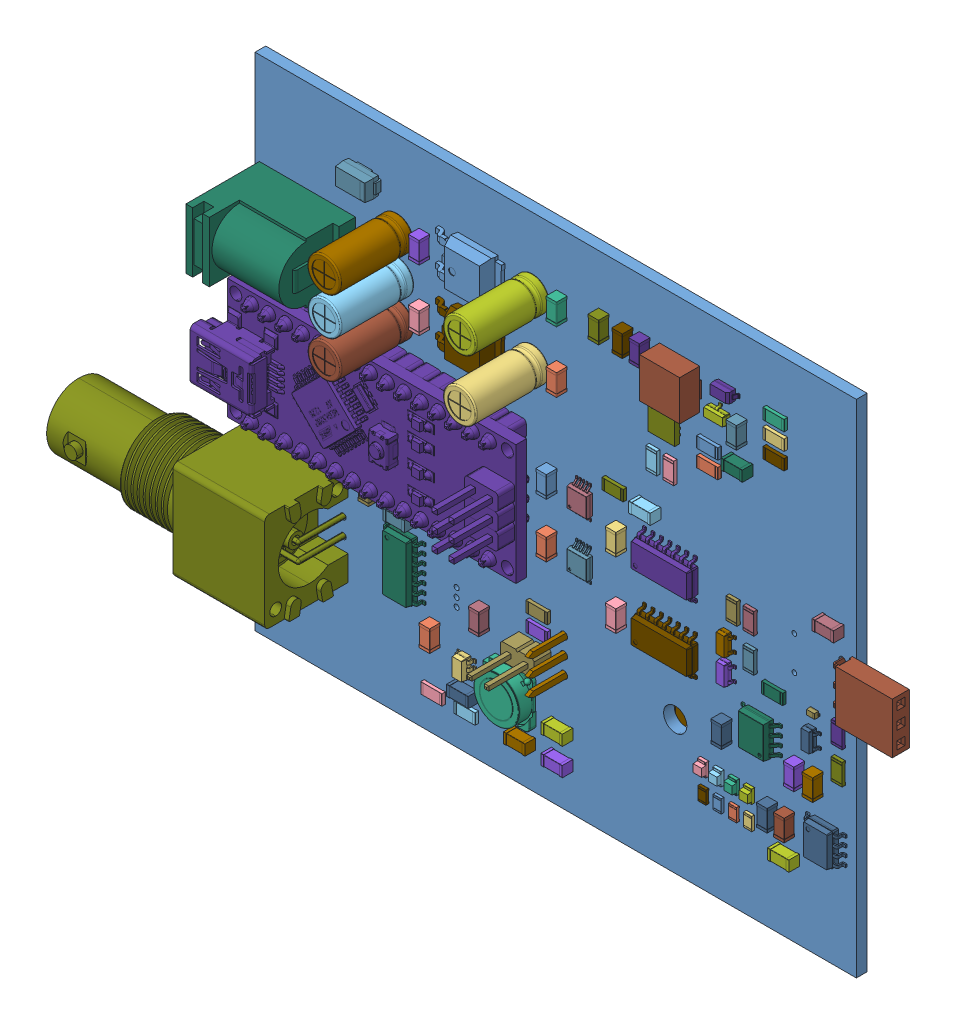
SolidWorks assembly PCB assembly, configuration Domyślna. Lengths in mm.
Overall size (117.64 75 20.3).
95 component instances, 91 part files, 0 mates.
Components (placement in the parent):
- PCB assembly.step-1: PCB assembly.step [Domyślna] at origin size (117.64 75 20.3)
  - Board_Geoms_e78a.step-1: Board_Geoms_e78a.step [Domyślna] at origin size (90 75 1.6)
    - Pcb_e78a.step-1: Pcb_e78a.step [Domyślna] at (-104.194 136.428 0) size (90 75 1.6)
    - PCB_Sketch_e78a.step-1: PCB_Sketch_e78a.step [Domyślna] at origin (suppressed, hidden)
  - Step_Models_e78a.step-1: Step_Models_e78a.step [Domyślna] at origin size (117.64 63.77 20.3)
    - Top_e78a.step-1: Top_e78a.step [Domyślna] at origin size (117.64 63.77 20.3)
      - C31_C_1206_3216Metric_5F0E55A1.step-1: C31_C_1206_3216Metric_5F0E55A1.step [Domyślna] at (26.924 3.302 0) x (0 -1 0) z (0 0 1) size (3.2 1.6 1.6)
      - IC12_SOT_23_6_5F31C27B.step-1: IC12_SOT_23_6_5F31C27B.step [Domyślna] at (31.75 1.651 0) x (-1 0 0) z (0 0 1) size (2.8 2.9 1.55)
      - R23_R_1206_3216Metric_5F31C265.step-1: R23_R_1206_3216Metric_5F31C265.step [Domyślna] at (26.924 -4.445 0) size (3.2 1.6 0.55)
      - R22_R_1206_3216Metric_5F31DD4A.step-1: R22_R_1206_3216Metric_5F31DD4A.step [Domyślna] at (31.877 -4.445 0) x (-1 0 0) z (0 0 1) size (3.2 1.6 0.55)
      - L2_Sf_fd_sp_5F31CDB4[2].step-1: L2_Sf_fd_sp_5F31CDB4[2].step [Domyślna] at (38.608 1.651 0.0508) size (7 7 2.5)
      - C36_C_1206_3216Metric_5F31B990.step-1: C36_C_1206_3216Metric_5F31B990.step [Domyślna] at (45.974 0.381 0) size (3.2 1.6 1.6)
      - C35_C_1206_3216Metric_5F31B97F.step-1: C35_C_1206_3216Metric_5F31B97F.step [Domyślna] at (45.974 -3.683 0) size (3.2 1.6 1.6)
      - C34_C_1206_3216Metric_5F31B96E.step-1: C34_C_1206_3216Metric_5F31B96E.step [Domyślna] at (40.386 -3.683 0) x (-1 0 0) z (0 0 1) size (3.2 1.6 1.6)
      - C33_C_1206_3216Metric_5F31B95D.step-1: C33_C_1206_3216Metric_5F31B95D.step [Domyślna] at (31.877 -1.778 0) x (-1 0 0) z (0 0 1) size (3.2 1.6 1.6)
      - C32_C_1206_3216Metric_5F2DB7B1.step-1: C32_C_1206_3216Metric_5F2DB7B1.step [Domyślna] at (5.334 24.384 0) x (-1 0 0) z (0 0 1) size (3.2 1.6 1.6)
      - R21_R_1206_3216Metric_5F2CE966.step-1: R21_R_1206_3216Metric_5F2CE966.step [Domyślna] at (42.672 13.97 0) size (3.2 1.6 0.55)
      - IC8_DS1124U-25+_5F0C9A39.step-1: IC8_DS1124U-25+_5F0C9A39.step [Domyślna] at (49.222 31.78 0) x (0 1 0) z (0 0 1) size (4.9 3 1.1)
      - IC7_DS1124U-25+_5F0C50CD.step-1: IC7_DS1124U-25+_5F0C50CD.step [Domyślna] at (49.222 23.652 0) x (0 1 0) z (0 0 1) size (4.9 3 1.1)
      - IC2_TLV3501AIDR_5F0DC31C.step-1: IC2_TLV3501AIDR_5F0DC31C.step [Domyślna] at (75.944 15.19 0) x (-1 0 0) z (0 0 1) size (6 4.9 1.75)
      - IC1_MAX1932ETC+_5F0DC301.step-1: IC1_MAX1932ETC+_5F0DC301.step [Domyślna] at (61.614 48.076 0) size (4.1 4.1 0.8)
      - D1_BAT46W-E3-08_5F0B6668.step-1: D1_BAT46W-E3-08_5F0B6668.step [Domyślna] at (70.758 56.712 0) x (-1 0 0) z (0 0 1) size (3.7 1.55 1.35)
      - R20_R_0805_2012Metric_5F2C1AB9.step-1: R20_R_0805_2012Metric_5F2C1AB9.step [Domyślna] at (67.31 2.54 0) x (0 -1 0) z (0 0 1) size (2 1.2 0.45)
      - R19_R_0805_2012Metric_5F2C1B19.step-1: R19_R_0805_2012Metric_5F2C1B19.step [Domyślna] at (69.596 2.54 0) x (0 -1 0) z (0 0 1) size (2 1.2 0.45)
      - R16_R_0805_2012Metric_5F2C1B49.step-1: R16_R_0805_2012Metric_5F2C1B49.step [Domyślna] at (71.882 2.54 0) x (0 -1 0) z (0 0 1) size (2 1.2 0.45)
      - R13_R_0805_2012Metric_5F2C1AE9.step-1: R13_R_0805_2012Metric_5F2C1AE9.step [Domyślna] at (74.168 2.54 0) x (0 -1 0) z (0 0 1) size (2 1.2 0.45)
      - D8_LED_0805_2012Metric_5F2C1BB1.step-1: D8_LED_0805_2012Metric_5F2C1BB1.step [Domyślna] at (67.31 6.096 0) x (0 1 0) z (0 0 1) size (2 1.25 1.1)
      - D7_LED_0805_2012Metric_5F2C1BE7.step-1: D7_LED_0805_2012Metric_5F2C1BE7.step [Domyślna] at (69.596 6.096 0) x (0 1 0) z (0 0 1) size (2 1.25 1.1)
      - D6_LED_0805_2012Metric_5F2C1B7B.step-1: D6_LED_0805_2012Metric_5F2C1B7B.step [Domyślna] at (71.882 6.096 0) x (0 1 0) z (0 0 1) size (2 1.25 1.1)
      - D5_LED_0805_2012Metric_5F2B9F6D.step-1: D5_LED_0805_2012Metric_5F2B9F6D.step [Domyślna] at (74.168 6.096 0) x (0 1 0) z (0 0 1) size (2 1.25 1.1)
      - R10_R_1206_3216Metric_5F2BA4CF.step-1: R10_R_1206_3216Metric_5F2BA4CF.step [Domyślna] at (42.672 11.43 0) size (3.2 1.6 0.55)
      - Q5_TO-220-3_Horizontal_TabUp_5F0F3956.step-1: Q5_TO-220-3_Horizontal_TabUp_5F0F3956.step [Domyślna] at (46.228 12.5 -2.54) x (0 -1 0) z (0 0 -1) size (10.25 19.74 12.58)
      - IC5_SOIC_8_39x49mm_P127mm_5F2C782A.step-1: IC5_SOIC_8_39x49mm_P127mm_5F2C782A.step [Domyślna] at (85.598 5.788 0) size (6 4.9 1.75)
      - C30_C_Radial_D50mm_H110mm_P200mm_5F0E5590.step-1: C30_C_Radial_D50mm_H110mm_P200mm_5F0E5590.step [Domyślna] at (21.336 42.164 0) x (0 -1 0) z (0 0 1) size (6.29 6.83 13)
      - J2_PinHeader_1x02_P254mm_Vertical_5F2D0180.step-1: J2_PinHeader_1x02_P254mm_Vertical_5F2D0180.step [Domyślna] at (40.513 8.382 0) x (0 1 0) z (0 0 1) size (2.54 5.08 11.54)
      - C29_C_1206_3216Metric_5F0F3A25.step-1: C29_C_1206_3216Metric_5F0F3A25.step [Domyślna] at (34.29 9.144 0) x (0 -1 0) z (0 0 1) size (3.2 1.6 1.6)
      - C28_C_1206_3216Metric_5F0EE626.step-1: C28_C_1206_3216Metric_5F0EE626.step [Domyślna] at (22.352 16.256 0) x (-1 0 0) z (0 0 1) size (3.2 1.6 1.6)
      - IC10_SOIC_14_39x87mm_P127mm_5F0D8E3B.step-1: IC10_SOIC_14_39x87mm_P127mm_5F0D8E3B.step [Domyślna] at (22.617 10.19 0) size (6 8.7 1.75)
      - R9_R_1206_3216Metric_5F0C53DD.step-1: R9_R_1206_3216Metric_5F0C53DD.step [Domyślna] at (54.048 35.59 0) size (3.2 1.6 0.55)
      - IC9_SOIC_14_39x87mm_P127mm_5F0C510A.step-1: IC9_SOIC_14_39x87mm_P127mm_5F0C510A.step [Domyślna] at (62.176 29.748 0) x (0 1 0) z (0 0 1) size (6 8.7 1.75)
      - IC6_SOIC_14_39x87mm_P127mm_5F0C50B0.step-1: IC6_SOIC_14_39x87mm_P127mm_5F0C50B0.step [Domyślna] at (62.176 19.842 0) x (0 1 0) z (0 0 1) size (6 8.7 1.75)
      - C27_C_1206_3216Metric_5F0C4ED7.step-1: C27_C_1206_3216Metric_5F0C4ED7.step [Domyślna] at (44.396 32.034 0) x (0 -1 0) z (0 0 1) size (3.2 1.6 1.6)
      - C26_C_1206_3216Metric_5F0C4EC6.step-1: C26_C_1206_3216Metric_5F0C4EC6.step [Domyślna] at (44.396 23.906 0) x (0 -1 0) z (0 0 1) size (3.2 1.6 1.6)
      - C25_C_1206_3216Metric_5F0C4EB5.step-1: C25_C_1206_3216Metric_5F0C4EB5.step [Domyślna] at (54.81 29.748 0) x (0 -1 0) z (0 0 1) size (3.2 1.6 1.6)
      - C24_C_1206_3216Metric_5F0C4EA4.step-1: C24_C_1206_3216Metric_5F0C4EA4.step [Domyślna] at (54.81 19.842 0) x (0 -1 0) z (0 0 1) size (3.2 1.6 1.6)
      - C23_C_1206_3216Metric_5F0C4E93.step-1: C23_C_1206_3216Metric_5F0C4E93.step [Domyślna] at (59.128 35.59 0) size (3.2 1.6 1.6)
      - R4_R_1206_3216Metric_5F0BCC0F.step-1: R4_R_1206_3216Metric_5F0BCC0F.step [Domyślna] at (33.474 24.414 0) size (3.2 1.6 0.55)
      - C22_C_1206_3216Metric_5F2C77F1.step-1: C22_C_1206_3216Metric_5F2C77F1.step [Domyślna] at (79.886 1.016 0) x (-1 0 0) z (0 0 1) size (3.2 1.6 1.6)
      - C21_C_1206_3216Metric_5F0BC811.step-1: C21_C_1206_3216Metric_5F0BC811.step [Domyślna] at (81.452 12.646 0) x (0 -1 0) z (0 0 1) size (3.2 1.6 1.6)
      - C20_C_1206_3216Metric_5F0BC800.step-1: C20_C_1206_3216Metric_5F0BC800.step [Domyślna] at (84.246 12.646 0) x (0 -1 0) z (0 0 1) size (3.2 1.6 1.6)
      - C19_C_1206_3216Metric_5F2C7791.step-1: C19_C_1206_3216Metric_5F2C7791.step [Domyślna] at (77.44 5.28 0) x (0 -1 0) z (0 0 1) size (3.2 1.6 1.6)
      - C18_C_1206_3216Metric_5F2C77C1.step-1: C18_C_1206_3216Metric_5F2C77C1.step [Domyślna] at (79.98 5.28 0) x (0 -1 0) z (0 0 1) size (3.2 1.6 1.6)
      - C17_C_1206_3216Metric_5F0BB606.step-1: C17_C_1206_3216Metric_5F0BB606.step [Domyślna] at (17.78 17.78 0) x (0 -1 0) z (0 0 1) size (3.2 1.6 1.6)
      - C16_C_1206_3216Metric_5F0BBC4D.step-1: C16_C_1206_3216Metric_5F0BBC4D.step [Domyślna] at (33.728 18.572 0) size (3.2 1.6 1.6)
      - D4_D_SMA_5F0B762E.step-1: D4_D_SMA_5F0B762E.step [Domyślna] at (16.456 57.18 0) x (-1 0 0) z (0 0 1) size (5 2.7 2.22)
      - J4_CUI_DEVICES_PJ-102AH_5F0EDE56.step-1: J4_CUI_DEVICES_PJ-102AH_5F0EDE56.step [Domyślna] at (0.7334 46.736 6.5786) x (-1 0 0) z (0 1 0) size (14.4 14.5 9.4)
      - J3_73100-0131_5F0BBBC4.step-1: J3_73100-0131_5F0BBBC4.step [Domyślna] at (-2.4892 11.43 6.6548) x (0 -1 0) z (-1 0 0) size (14.76 18.23 35.18)
      - A1_arduino_nano_5F2D0076.step-1: A1_arduino_nano_5F2D0076.step [Domyślna] at (39.824 36.86 3) x (-1 0 0) z (0 1 0) size (45 18.6 18)
      - IC4_TO_252_2_5F0B63C8.step-1: IC4_TO_252_2_5F0B63C8.step [Domyślna] at (32.458 44.48 0) size (9.9 6.5 2.32)
      - IC3_TO_252_2_5F0B6491.step-1: IC3_TO_252_2_5F0B6491.step [Domyślna] at (32.458 53.624 0) size (9.9 6.5 2.32)
      - C15_C_1206_3216Metric_5F0B641E.step-1: C15_C_1206_3216Metric_5F0B641E.step [Domyślna] at (45.92 46.004 0) x (0 1 0) z (0 0 1) size (3.2 1.6 1.6)
      - C14_C_Radial_D50mm_H110mm_P200mm_5F0B62A3.step-1: C14_C_Radial_D50mm_H110mm_P200mm_5F0B62A3.step [Domyślna] at (41.602 44.48 0) x (0 1 0) z (0 0 1) size (6.29 6.83 13)
      - C13_C_1206_3216Metric_5F0B644E.step-1: C13_C_1206_3216Metric_5F0B644E.step [Domyślna] at (25.346 43.718 0) x (0 1 0) z (0 0 1) size (3.2 1.6 1.6)
      - C12_C_Radial_D50mm_H110mm_P200mm_5F0B62BE.step-1: C12_C_Radial_D50mm_H110mm_P200mm_5F0B62BE.step [Domyślna] at (21.336 45.72 0) x (0 1 0) z (0 0 1) size (6.29 6.83 13)
      - C11_C_1206_3216Metric_5F0B62E0.step-1: C11_C_1206_3216Metric_5F0B62E0.step [Domyślna] at (45.92 55.148 0) x (0 1 0) z (0 0 1) size (3.2 1.6 1.6)
      - C10_C_Radial_D50mm_H110mm_P200mm_5F0B6309.step-1: C10_C_Radial_D50mm_H110mm_P200mm_5F0B6309.step [Domyślna] at (41.602 53.624 0) x (0 1 0) z (0 0 1) size (6.29 6.83 13)
      - C9_C_1206_3216Metric_5F0B6385.step-1: C9_C_1206_3216Metric_5F0B6385.step [Domyślna] at (25.346 52.862 0) x (0 1 0) z (0 0 1) size (3.2 1.6 1.6)
      - C8_C_Radial_D50mm_H110mm_P200mm_5F0B6324.step-1: C8_C_Radial_D50mm_H110mm_P200mm_5F0B6324.step [Domyślna] at (21.282 51.338 0) x (0 1 0) z (0 0 1) size (6.29 6.83 13)
      - C7_C_1206_3216Metric_5F0C274F.step-1: C7_C_1206_3216Metric_5F0C274F.step [Domyślna] at (70.61 12.7 0) x (0 -1 0) z (0 0 1) size (3.2 1.6 1.6)
      - J1_PinSocket_1x03_P254mm_Horizontal_5F0B7F2C.step-1: J1_PinSocket_1x03_P254mm_Horizontal_5F0B7F2C.step [Domyślna] at (87.884 25.019 0) x (-1 0 0) z (0 0 1) size (10.13 7.62 5.84)
      - R18_R_1206_3216Metric_5F0A53A7.step-1: R18_R_1206_3216Metric_5F0A53A7.step [Domyślna] at (71.828 28.732 0) x (0 1 0) z (0 0 1) size (3.2 1.6 0.55)
      - R17_R_1206_3216Metric_5F0A5396.step-1: R17_R_1206_3216Metric_5F0A5396.step [Domyślna] at (74.368 28.732 0) x (0 1 0) z (0 0 1) size (3.2 1.6 0.55)
      - R15_R_1206_3216Metric_5F0A5385.step-1: R15_R_1206_3216Metric_5F0A5385.step [Domyślna] at (74.368 23.652 0) x (0 -1 0) z (0 0 1) size (3.2 1.6 0.55)
      - R14_R_1206_3216Metric_5F0A5374.step-1: R14_R_1206_3216Metric_5F0A5374.step [Domyślna] at (77.924 21.112 0) size (3.2 1.6 0.55)
      - R12_R_1206_3216Metric_5F0A5363.step-1: R12_R_1206_3216Metric_5F0A5363.step [Domyślna] at (87.576 15.778 0) x (0 -1 0) z (0 0 1) size (3.2 1.6 0.55)
      - R11_R_1206_3216Metric_5F0D1442.step-1: R11_R_1206_3216Metric_5F0D1442.step [Domyślna] at (87.576 20.604 0) x (0 -1 0) z (0 0 1) size (3.2 1.6 0.55)
      - R8_R_1206_3216Metric_5F0B69A0.step-1: R8_R_1206_3216Metric_5F0B69A0.step [Domyślna] at (78.124 51.632 0) size (3.2 1.6 0.55)
      - R7_R_1206_3216Metric_5F0B6970.step-1: R7_R_1206_3216Metric_5F0B6970.step [Domyślna] at (68.218 48.076 0) size (3.2 1.6 0.55)
      - R6_R_1206_3216Metric_5F0B680B.step-1: R6_R_1206_3216Metric_5F0B680B.step [Domyślna] at (68.218 45.536 0) x (-1 0 0) z (0 0 1) size (3.2 1.6 0.55)
      - R5_R_1206_3216Metric_5F0B67AB.step-1: R5_R_1206_3216Metric_5F0B67AB.step [Domyślna] at (78.124 54.172 0) x (-1 0 0) z (0 0 1) size (3.2 1.6 0.55)
      - R3_R_1206_3216Metric_5F0B6940.step-1: R3_R_1206_3216Metric_5F0B6940.step [Domyślna] at (62.376 42.234 0) x (0 1 0) z (0 0 1) size (3.2 1.6 0.55)
      - R2_R_1206_3216Metric_5F0B6910.step-1: R2_R_1206_3216Metric_5F0B6910.step [Domyślna] at (59.836 42.234 0) x (0 -1 0) z (0 0 1) size (3.2 1.6 0.55)
      - R1_R_1206_3216Metric_5F0B68E0.step-1: R1_R_1206_3216Metric_5F0B68E0.step [Domyślna] at (78.124 56.712 0) size (3.2 1.6 0.55)
      - Q4_SOT_23_5F0B68A8.step-1: Q4_SOT_23_5F0B68A8.step [Domyślna] at (69.742 53.156 0) x (0 1 0) z (0 0 1) size (2.5 3 1.2)
      - Q3_SOT_23_5F0B91D4.step-1: Q3_SOT_23_5F0B91D4.step [Domyślna] at (70.812 20.35 0) x (-1 0 0) z (0 0 1) size (2.5 3 1.2)
      - Q2_SOT_23_5F0B9198.step-1: Q2_SOT_23_5F0B9198.step [Domyślna] at (70.812 24.16 0) x (-1 0 0) z (0 0 1) size (2.5 3 1.2)
      - Q1_SOT_23_5F0A528B.step-1: Q1_SOT_23_5F0A528B.step [Domyślna] at (83.512 18.064 0) x (-1 0 0) z (0 0 1) size (2.5 3 1.2)
      - L1_#A921CY-101M=P3_5F0B67DB.step-1: L1_#A921CY-101M=P3_5F0B67DB.step [Domyślna] at (63.646 54.68 0) size (6.4 6 3.1)
      - D2_D_SOD_523_5F0A520A.step-1: D2_D_SOD_523_5F0A520A.step [Domyślna] at (83.766 21.366 0) x (-1 0 0) z (0 0 1) size (1.6 0.8 0.63)
      - C6_C_1206_3216Metric_5F0A72A1.step-1: C6_C_1206_3216Metric_5F0A72A1.step [Domyślna] at (86.56 34.066 0) size (3.2 1.6 1.6)
      - C5_C_1206_3216Metric_5F0A51C2.step-1: C5_C_1206_3216Metric_5F0A51C2.step [Domyślna] at (72.844 52.608 0) x (0 1 0) z (0 0 1) size (3.2 1.6 1.6)
      - C4_C_1206_3216Metric_5F0B66CA.step-1: C4_C_1206_3216Metric_5F0B66CA.step [Domyślna] at (72.914 48.076 0) x (-1 0 0) z (0 0 1) size (3.2 1.6 1.6)
      - C3_C_1206_3216Metric_5F0B66FA.step-1: C3_C_1206_3216Metric_5F0B66FA.step [Domyślna] at (52.216 55.95 0) x (0 1 0) z (0 0 1) size (3.2 1.6 1.6)
      - C2_C_1206_3216Metric_5F0B669A.step-1: C2_C_1206_3216Metric_5F0B669A.step [Domyślna] at (58.312 55.95 0) x (0 1 0) z (0 0 1) size (3.2 1.6 1.6)
      - C1_C_1206_3216Metric_5F0B677B.step-1: C1_C_1206_3216Metric_5F0B677B.step [Domyślna] at (55.772 55.95 0) x (0 1 0) z (0 0 1) size (3.2 1.6 1.6)
